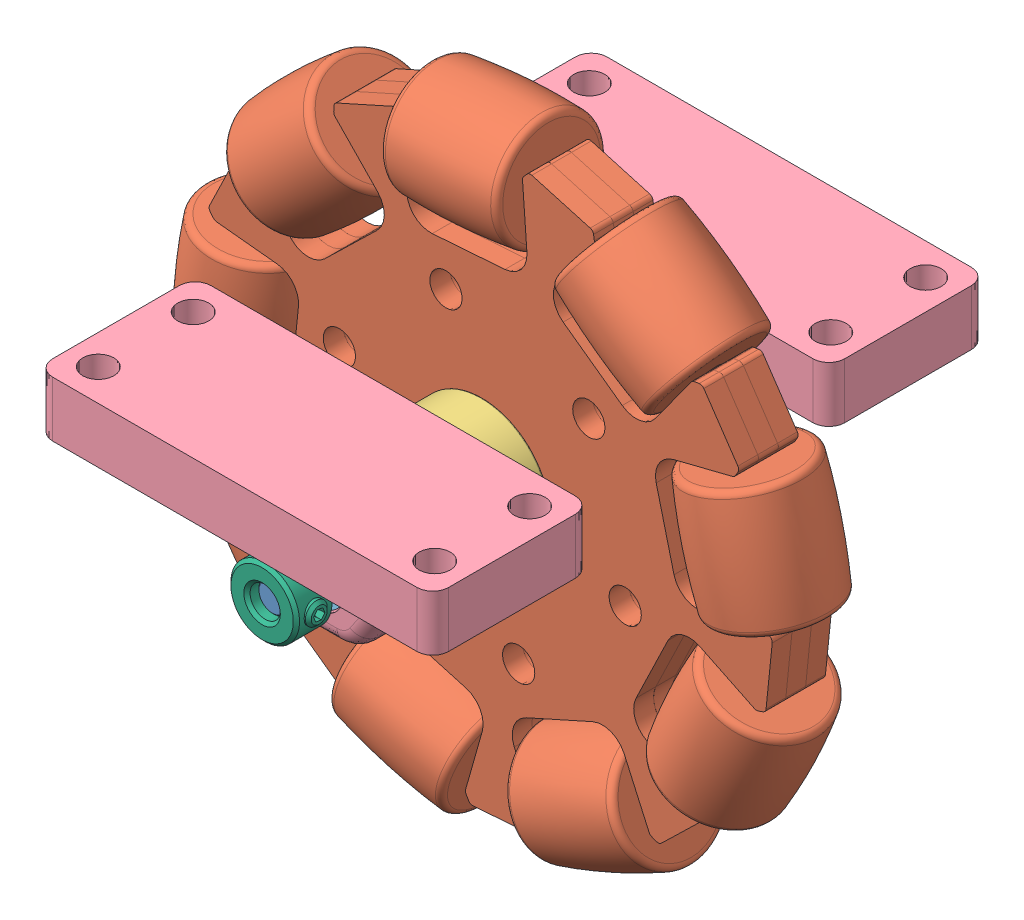
SolidWorks assembly Omniwheel set, configuration Default. Lengths in mm.
Overall size (140.97 139.61 88.9).
9 component instances, 6 part files, 22 mates.
Components (placement in the parent):
- 3in_Axel-1: 3in_Axel [Default] at (2.413 -2.413 -76.2) x (0.958428 0.285334 0) z (0.285334 -0.958428 0) size (4.83 76.2 4.83)
- 4 inch omniwheel-2: 4 inch omniwheel [Default] at (5.0047 -4.3489 -46.041) x (-0.696661 0.7174 0) z (-0.7174 -0.696661 0) size (103.44 22.06 104.38)
- 39079_txm-motor shaft hub with set screw-1: 39079_txm-motor shaft hub with set screw [Default] at (16.4027 7.2046 -45.1063) x (-0.696661 0.7174 0) z (0 0 1) size (22 22 9.4)
- Omniwheel block-1: Omniwheel block [Default] at (2.413 16.637 -57.4712) x (1 0 0) z (0 1 0) size (63.5 25.4 27.33)
- Wheel bushing-1: Wheel bushing [Default] at (-0.0381 -2.413 -57.046) size (9.52 9.53 12.7)
- 39092_txm-axlesetcollars-1: 39092_txm-axlesetcollars [Default] at (2.6462 -2.783 -72.9038) x (0.992781 0.11994 0) z (0 0 1) size (11.66 11 6.2)
- Omniwheel block-2: Omniwheel block [Default] at (2.413 16.637 -19.3712) x (-1 0 0) z (0 1 0) size (63.5 25.4 27.33)
- Wheel bushing-2: Wheel bushing [Default] at (-0.0381 -2.413 -19.7964) x (1 0 0) z (0 0 -1) size (9.52 9.53 12.7)
- 39092_txm-axlesetcollars-2: 39092_txm-axlesetcollars [Default] at (2.6002 -2.8083 -1.2602) size (11.66 11 6.2)
Mates (geometry in assembly coordinates):
- Tangent1: tangent aligned: cylinder of 3in_Axel-1 through (2.413 -2.413 0) axis (0 0 -1) radius 2.413; plane of assembly through (0 0 0) normal (0 1 0)
- Coincident1: coincident aligned: plane of 3in_Axel-1 through (2.413 -2.413 0) normal (0 0 1); plane of assembly through (0 0 0) normal (0 0 1)
- Tangent2: tangent anti-aligned: cylinder of 3in_Axel-1 through (2.413 -2.413 0) axis (0 0 -1) radius 2.413; plane of assembly through (0 0 0) normal (1 0 0)
- Concentric1: concentric aligned: cylinder of 4 inch omniwheel-2 through (2.413 -2.413 -77.2269) axis (0 0 1) radius 4; cylinder of 39079_txm-motor shaft hub with set screw-1 through (2.413 -2.413 -33.6587) axis (0 0 1) radius 3.015
- Concentric2: concentric aligned: cylinder of 4 inch omniwheel-2 through (-3.3262 -7.9863 -77.2269) axis (0 0 1) radius 2; cylinder of 39079_txm-motor shaft hub with set screw-1 through (-3.3262 -7.9863 -33.6587) axis (0 0 1) radius 1.35
- Coincident2: coincident anti-aligned: plane of 4 inch omniwheel-2 through (35.5922 -11.9902 -33.6587) normal (0 0 1); plane of 39079_txm-motor shaft hub with set screw-1 through (2.413 -2.413 -33.6587) normal (0 0 -1)
- Concentric3: concentric anti-aligned: cylinder of 3in_Axel-1 through (2.413 -2.413 0) axis (0 0 -1) radius 2.413; cylinder of 39079_txm-motor shaft hub with set screw-1 through (2.413 -2.413 -33.6587) axis (0 0 1) radius 3.015
- Concentric4: concentric anti-aligned: cylinder of Omniwheel block-1 through (2.413 -2.413 -82.8712) axis (0 0 1) radius 4.375; cylinder of Wheel bushing-1 through (2.413 -2.413 -69.746) axis (0 0 -1) radius 3.937
- Coincident3: coincident anti-aligned: plane of Omniwheel block-1 through (2.413 -2.413 -68.1712) normal (0 0 -1); plane of Wheel bushing-1 through (-0.0381 -2.413 -68.1712) normal (0 0 1)
- Concentric5: concentric aligned: cylinder of 3in_Axel-1 through (2.413 -2.413 0) axis (0 0 -1) radius 2.413; cylinder of Wheel bushing-1 through (2.413 -2.413 -69.746) axis (0 0 -1) radius 2.4511
- Parallel1: parallel aligned: plane of Omniwheel block-1 through (34.163 16.637 -82.8712) normal (0 1 0); plane of assembly through (0 0 0) normal (0 1 0)
- Concentric6: concentric anti-aligned: cylinder of 3in_Axel-1 through (2.413 -2.413 0) axis (0 0 -1) radius 2.413; cylinder of 39092_txm-axlesetcollars-1 through (2.413 -2.413 -76.2) axis (0 0 1) radius 2.425
- Coincident6: coincident aligned: plane of 3in_Axel-1 through (2.413 -2.413 -76.2) normal (0 0 -1); plane of 39092_txm-axlesetcollars-1 through (2.413 -2.413 -76.2) normal (0 0 -1)
- Distance1: distance = 0.254 mm anti-aligned: plane of Wheel bushing-1 through (-0.0381 -2.413 -69.746) normal (0 0 -1); plane of 39092_txm-axlesetcollars-1 through (2.413 -2.413 -70) normal (0 0 1)
- Concentric7: concentric anti-aligned: cylinder of Omniwheel block-2 through (2.413 -2.413 6.0288) axis (0 0 -1) radius 4.375; cylinder of Wheel bushing-2 through (2.413 -2.413 -7.0964) axis (0 0 1) radius 3.937
- Coincident8: coincident anti-aligned: plane of Omniwheel block-2 through (2.413 -2.413 -8.6712) normal (0 0 1); plane of Wheel bushing-2 through (-0.0381 -2.413 -8.6712) normal (0 0 -1)
- Concentric8: concentric anti-aligned: cylinder of 3in_Axel-1 through (2.413 -2.413 0) axis (0 0 -1) radius 2.413; cylinder of Wheel bushing-2 through (2.413 -2.413 -7.0964) axis (0 0 1) radius 2.4511
- Coincident9: coincident aligned: plane of Omniwheel block-1 through (34.163 16.637 -82.8712) normal (0 1 0); plane of Omniwheel block-2 through (-29.337 16.637 6.0288) normal (0 1 0)
- Distance2: distance = 88.9 mm anti-aligned: plane of Omniwheel block-1 through (2.413 16.637 -82.8712) normal (0 0 -1); plane of Omniwheel block-2 through (2.413 16.637 6.0288) normal (0 0 1)
- Concentric9: concentric anti-aligned: cylinder of 3in_Axel-1 through (2.413 -2.413 0) axis (0 0 -1) radius 2.413; cylinder of 39092_txm-axlesetcollars-2 through (2.413 -2.413 -4.5564) axis (0 0 1) radius 2.425
- Distance3: distance = 2.54 mm anti-aligned: plane of Wheel bushing-2 through (-0.0381 -2.413 -7.0964) normal (0 0 1); plane of 39092_txm-axlesetcollars-2 through (2.413 -2.413 -4.5564) normal (0 0 -1)
- Width1: width anti-aligned: plane of Omniwheel block-1 through (2.413 16.637 -82.8712) normal (0 0 -1); plane of Omniwheel block-2 through (2.413 16.637 6.0288) normal (0 0 1); plane of 4 inch omniwheel-2 through (35.5922 -11.9902 -33.6587) normal (0 0 1); plane of 4 inch omniwheel-2 through (35.5922 -11.9902 -43.1837) normal (0 0 -1)
